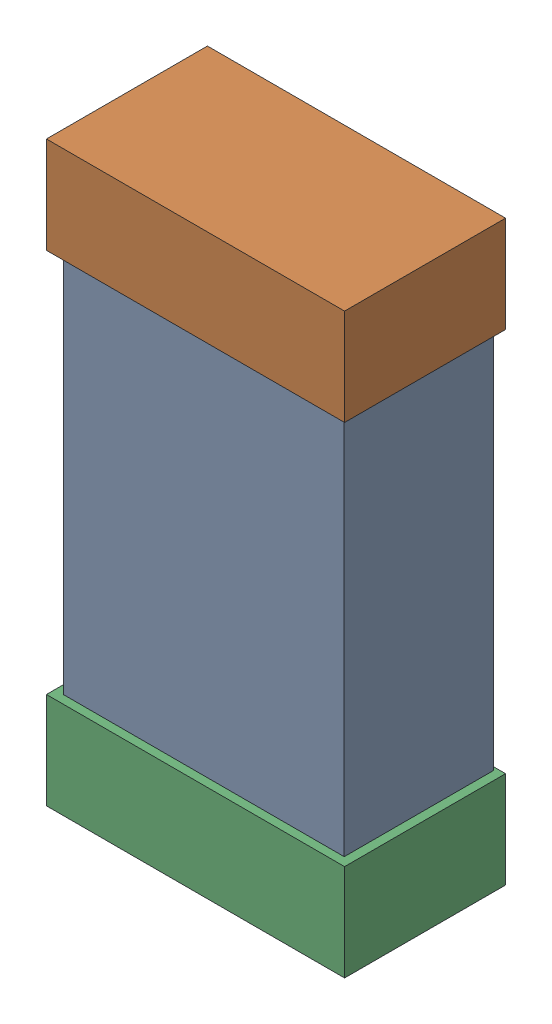
SolidWorks assembly R19, configuration Default. Lengths in mm.
Overall size (0.85 1.65 0.46).
6 component instances, 2 part files, 0 mates.
Components (placement in the parent):
- 432124816_51-1: 432124816_51 [Default] at (30.4166 43.4999 -0.8615) size (0.8 1.5 0.42)
  - Extruded (1)-1: Extruded (1) [Default] at origin size (0.8 1.5 0.42)
- 432138512_102-1: 432138512_102 [Default] at (30.4166 44.1857 -0.8715) size (0.85 0.28 0.46)
  - Extruded-1: Extruded [Default] at origin size (0.85 0.28 0.46)
- 432138512_103-1: 432138512_103 [Default] at (30.4166 42.8142 -0.8715) size (0.85 0.28 0.46)
  - Extruded-1: Extruded [Default] at origin size (0.85 0.28 0.46)
